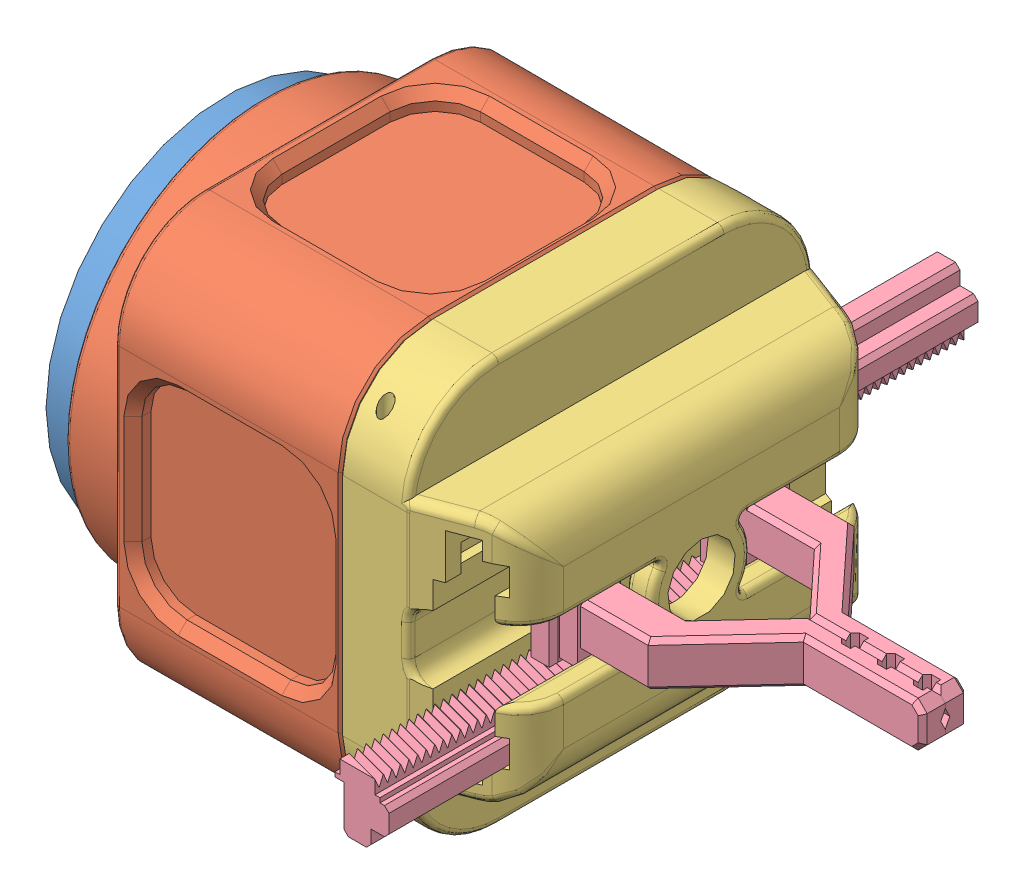
SolidWorks assembly grip-tool-model, configuration Default. Lengths in mm.
Overall size (159.24 90 130.5).
5 component instances, 4 part files, 9 mates.
Components (placement in the parent):
- connector imitation-2: connector imitation [Default] at origin size (10 80 80)
- case_link_2-1: case_link_2 [Default] at (8.24 0 0) x (0 0 -1) z (1 0 0) size (90 90 62)
- holder_link_2-1: holder_link_2 [Default] at (70.24 0 0) x (0 1 0) z (1 0 0) size (90 90.95 35)
- grip_link_3-1: grip_link_3 [Default] at (94.24 -16.5 65.25) x (0 0 -1) z (0 -1 0) size (90 72 32.75)
- grip_link_3-2: grip_link_3 [Default] at (94.24 16.5 -65.25) x (0 0 1) z (0 1 0) size (90 72 32.75)
Mates (geometry in assembly coordinates):
- Концентричный1: concentric aligned: cylinder of connector imitation-2 through (10 0 0) axis (-1 0 0) radius 40; cylinder of case_link_2-1 through (20.24 0 0) axis (-1 0 0) radius 40
- Расстояние1: distance = 8.24 mm aligned: plane of case_link_2-1 through (8.24 0 0) normal (-1 0 0); plane of connector imitation-2 through (0 0 0) normal (-1 0 0)
- Совпадение2: coincident anti-aligned: plane of case_link_2-1 through (70.24 -25 -25) normal (1 0 0); plane of holder_link_2-1 through (70.24 25 -25) normal (-1 0 0)
- Совпадение3: coincident aligned: plane of case_link_2-1 through (25.24 25 45) normal (0 0 1); plane of holder_link_2-1 through (80.24 25 45) normal (0 0 1)
- Совпадение4: coincident aligned: plane of case_link_2-1 through (25.24 45 25) normal (0 1 0); plane of holder_link_2-1 through (80.24 45 -25) normal (0 1 0)
- Совпадение5: coincident anti-aligned: plane of connector imitation-2 through (0 0 0) normal (0 0 1); plane of case_link_2-1 through (8.24 0 0) normal (0 0 -1)
- Совпадение6: coincident anti-aligned: plane of holder_link_2-1 through (91.24 -19.5 -45) normal (1 0 0); plane of grip_link_3-1 through (91.24 -23.5 -12.75) normal (-1 0 0)
- Совпадение7: coincident anti-aligned: plane of holder_link_2-1 through (91.24 -23.5 -45) normal (0 1 0); plane of grip_link_3-1 through (97.24 -23.5 -12.75) normal (0 -1 0)
- Совпадение8: coincident anti-aligned: plane of grip_link_3-1 through (121.24 -5 0) normal (0 0 1); plane of grip_link_3-2 through (121.24 5 0) normal (0 0 -1)
